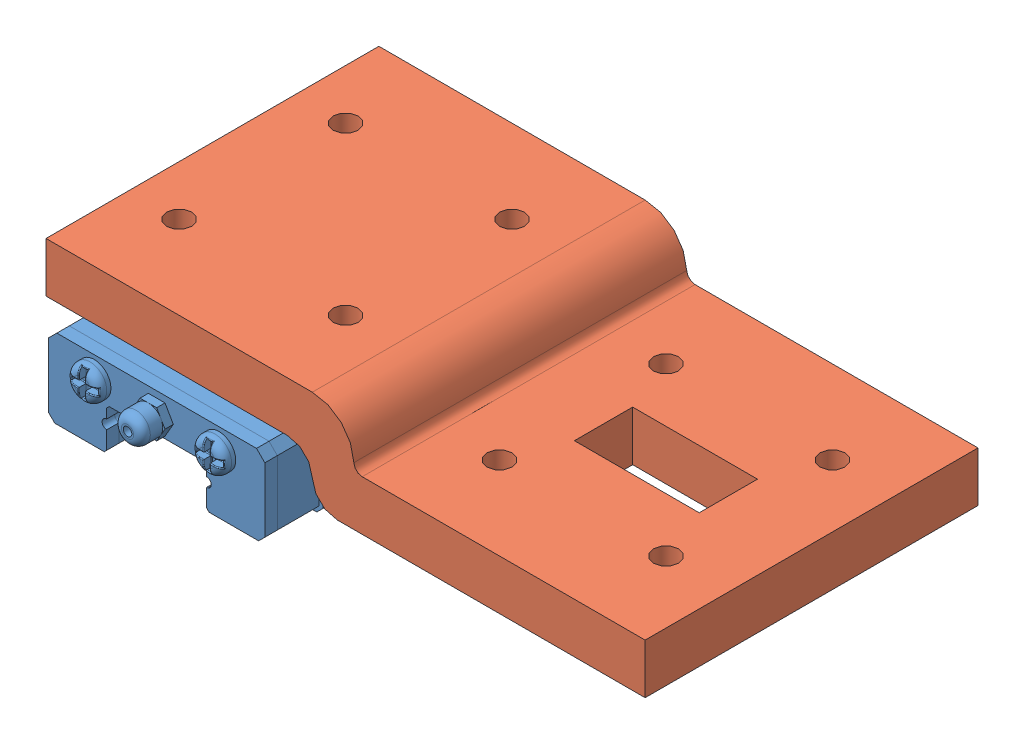
SolidWorks assembly Ползун с прямым зажимом, configuration По умолчанию. Lengths in mm.
Overall size (61 26.3 213).
2 component instances, 2 part files, 6 mates.
Components (placement in the parent):
- Ползун-1: Ползун [Default] at (0 -3 -38.9) size (27 10 50.47)
- Зажим плоский-1: Зажим плоский [По умолчанию] at (-16 10 -2.7) x (1 0 0) z (0 1 0) size (61 213 20.1)
Mates (geometry in assembly coordinates):
- Совпадение1: coincident anti-aligned: plane of Ползун-1 through (0 -3 -38.9) normal (-1 0 0); plane of assembly through (0 0 0) normal (1 0 0)
- Совпадение2: coincident anti-aligned: plane of Ползун-1 through (-13.5 0 -6.5) normal (0 -1 0); plane of assembly through (0 0 0) normal (0 1 0)
- Совпадение3: coincident aligned: plane of Ползун-1 through (6 3 0) normal (0 0 1); plane of assembly through (0 0 0) normal (0 0 1)
- Совпадение4: coincident anti-aligned: plane of Ползун-1 through (-13.5 10 -6.5) normal (0 1 0); plane of Зажим плоский-1 through (-16 10 -2.7) normal (0 -1 0)
- Концентричный1: concentric aligned: circle of Ползун-1; circle of Зажим плоский-1
- Концентричный2: concentric anti-aligned: cylinder of Ползун-1 through (-10 10 -12.7) axis (0 1 0) radius 1.25; cylinder of Зажим плоский-1 through (-10 14 -12.7) axis (0 -1 0) radius 1.5
